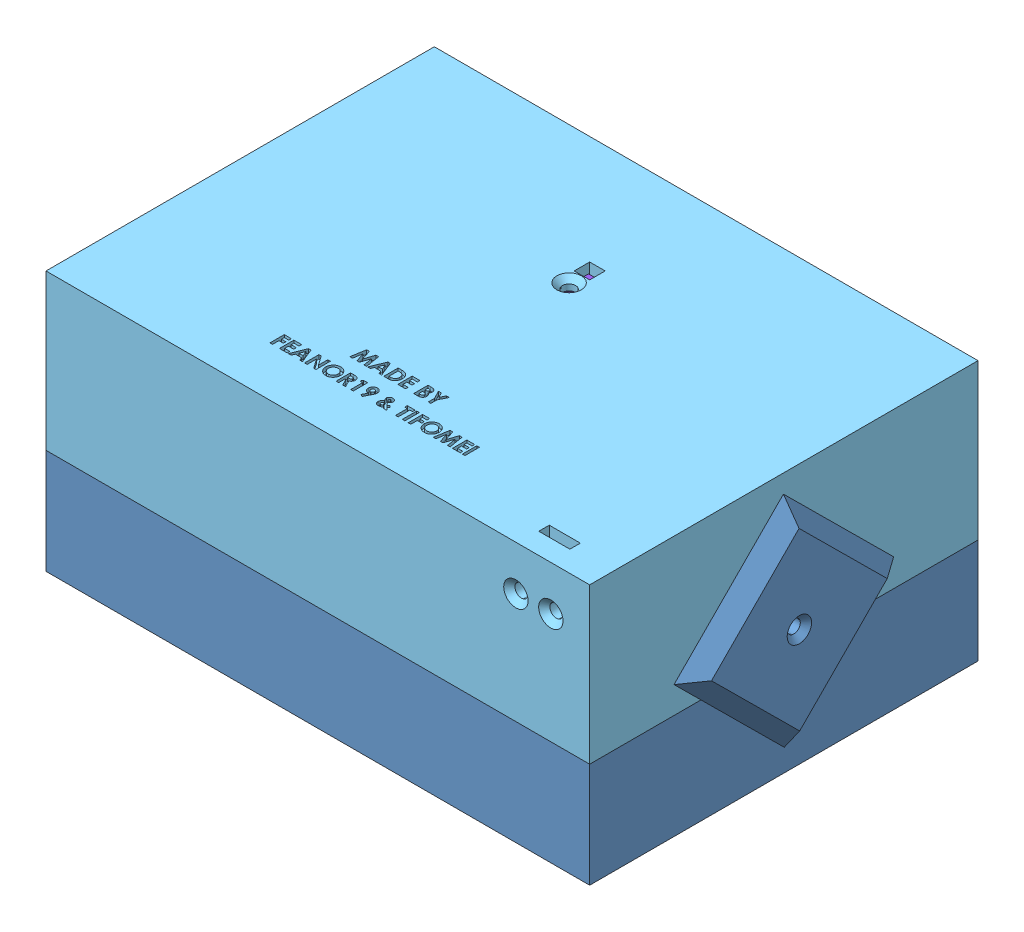
SolidWorks assembly Сборка, configuration По умолчанию. Lengths in mm.
Overall size (148 69.4 104).
9 component instances, 8 part files, 21 mates.
Components (placement in the parent):
- case_front-3: case_front [По умолчанию] at origin size (148 62.28 100)
- mock_display-2: mock_display [По умолчанию] at (70 8.6 -55) x (-1 0 0) z (0 0 1) size (98 24 60)
- mock_rgb_led-1: mock_rgb_led [По умолчанию] at (72 8.5 -13.8) x (0 0 1) z (1 0 0) size (15 5.5 11)
- mock_button-1: mock_button [По умолчанию] at (12 14.4 -88) x (1 0 0) z (0 1 0) size (14 15 14)
- mock_button-2: mock_button [По умолчанию] at (125.7 14.4 -88) x (1 0 0) z (0 1 0) size (14 15 14)
- case_back-1: case_back [По умолчанию] at (70 67 -50) x (-1 0 0) z (0 0 1) size (140 40 100)
- mock_CO2-3: mock_CO2 [По умолчанию] at (69.8 37.25 -91) x (1 0 0) z (0 1 0) size (39 8.7 19.7)
- case_grid-1: case_grid [По умолчанию] at (70 37.05 -100) x (0 1 0) z (-1 0 0) size (40 4 60)
- mock_bme-2: mock_bme [По умолчанию] at (74 62.5 -67.2) x (-1 0 0) z (0 0 -1) size (13 5 10)
Mates (geometry in assembly coordinates):
- Концентричный1: concentric aligned: circle of case_front-3; circle of mock_display-2
- Концентричный2: concentric aligned: cylinder of case_front-3 through (116.5 3 -27.5) axis (0 1 0) radius 2.225; circle of mock_display-2
- Совпадение5: coincident anti-aligned: plane of case_front-3 through (0 7 0) normal (0 1 0); plane of mock_display-2 through (70 7 -55) normal (0 -1 0)
- Концентричный3: concentric aligned: cylinder of case_front-3 through (75 3 -9.3) axis (0 1 0) radius 1.65; cylinder of mock_rgb_led-1 through (75 7 -9.3) axis (0 1 0) radius 1
- Совпадение6: coincident anti-aligned: plane of case_front-3 through (0 7 0) normal (0 1 0); plane of mock_rgb_led-1 through (72 7 -13.8) normal (0 -1 0)
- Совпадение7: coincident anti-aligned: plane of case_front-3 through (7 20.4 0.001) normal (0 -1 0); plane of mock_button-1 through (17 20.4 -100) normal (0 1 0)
- Совпадение8: coincident anti-aligned: plane of case_front-3 through (7 10 0.001) normal (1 0 0); plane of mock_button-1 through (7 8.4 -100) normal (-1 0 0)
- Совпадение9: coincident anti-aligned: plane of case_front-3 through (0 7 -100) normal (0 0 -1); plane of mock_button-1 through (12 14.4 -100) normal (0 0 1)
- Совпадение10: coincident anti-aligned: plane of case_front-3 through (133 20.4 0.001) normal (0 -1 0); plane of mock_button-2 through (130.7 20.4 -100) normal (0 1 0)
- Совпадение11: coincident anti-aligned: plane of case_front-3 through (120.7 10 0.001) normal (1 0 0); plane of mock_button-2 through (120.7 8.4 -100) normal (-1 0 0)
- Совпадение12: coincident anti-aligned: plane of case_front-3 through (0 7 -100) normal (0 0 -1); plane of mock_button-2 through (125.7 14.4 -100) normal (0 0 1)
- Концентричный4: concentric anti-aligned: circle of case_front-3; cylinder of case_back-1 through (140.001 34 -50) axis (-1 0 0) radius 2.225
- Концентричный5: concentric aligned: circle of case_front-3; cylinder of case_back-1 through (-0.001 34 -50) axis (1 0 0) radius 2.225
- Совпадение13: coincident aligned: plane of case_front-3 through (0 7 0) normal (-1 0 0); plane of case_back-1 through (0 63 -50) normal (-1 0 0)
- Совпадение15: coincident anti-aligned: plane of case_back-1 through (83.2 47.1 0.001) normal (0 -1 0); plane of mock_CO2-3 through (69.8 47.1 -99.7) normal (0 1 0)
- Совпадение16: coincident anti-aligned: plane of mock_CO2-3 through (69.8 37.25 -91) normal (0 0 1); plane of case_back-1 through (70 28 -91) normal (0 0 -1)
- Совпадение17: coincident anti-aligned: plane of case_back-1 through (56.8 47.1 0.001) normal (1 0 0); plane of mock_CO2-3 through (56.8 37.25 -99.7) normal (-1 0 0)
- Концентричный9: concentric aligned: cylinder of case_back-1 through (95 37.05 0.001) axis (0 0 -1) radius 2.225; cylinder of case_grid-1 through (95 37.05 -104) axis (0 0 -1) radius 1.7
- Совпадение18: coincident anti-aligned: plane of case_back-1 through (70 63 -100) normal (0 0 -1); plane of case_grid-1 through (70 37.05 -100) normal (0 0 1)
- Концентричный10: concentric anti-aligned: circle of case_back-1; circle of mock_bme-2
- Совпадение19: coincident anti-aligned: plane of case_back-1 through (70 64 -50) normal (0 -1 0); plane of mock_bme-2 through (74 64 -67.2) normal (0 1 0)
